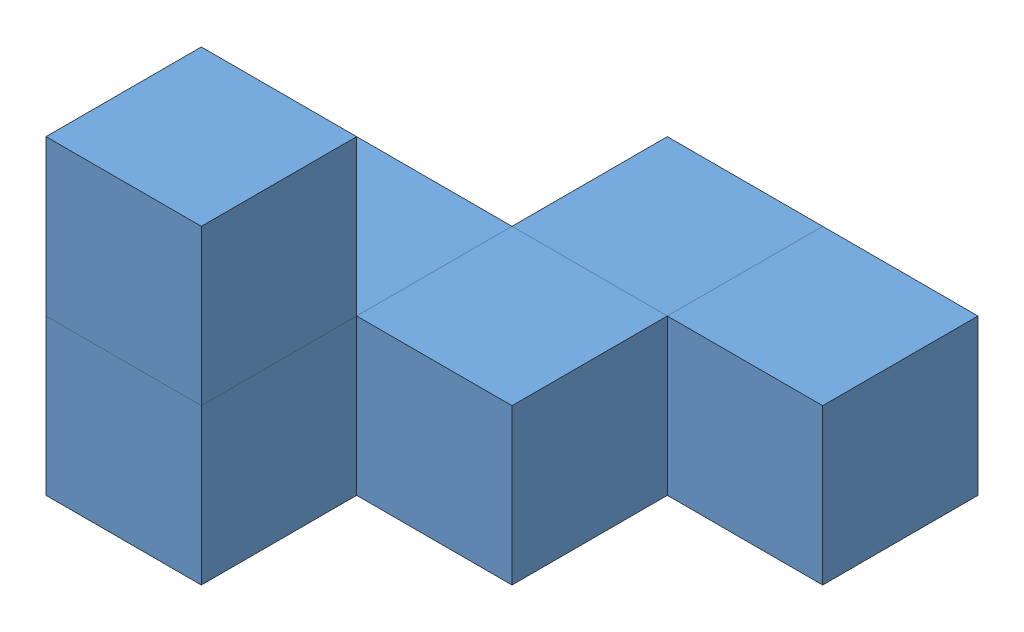
SolidWorks assembly Red Piece, configuration Default. Lengths in mm.
Overall size (60 40 60).
6 component instances, 1 part files, 18 mates.
Components (placement in the parent):
- cube-1: cube [Default] at (30 0 10) size (20 20 20)
- cube-2: cube [Default] at (30 0 30) size (20 20 20)
- cube-3: cube [Default] at (50 0 10) size (20 20 20)
- cube-4: cube [Default] at (10 0 50) size (20 20 20)
- cube-5: cube [Default] at (10 0 30) size (20 20 20)
- cube-6: cube [Default] at (10 20 50) size (20 20 20)
Mates (geometry in assembly coordinates):
- Coincident1: coincident aligned: plane of cube-1 through (40 20 20) normal (1 0 0); plane of cube-2 through (40 20 40) normal (1 0 0)
- Coincident2: coincident anti-aligned: plane of cube-1 through (40 20 20) normal (0 0 1); plane of cube-2 through (40 20 20) normal (0 0 -1)
- Coincident3: coincident aligned: plane of cube-1 through (30 20 10) normal (0 1 0); plane of cube-2 through (30 20 30) normal (0 1 0)
- Coincident4: coincident anti-aligned: plane of cube-2 through (20 20 40) normal (-1 0 0); plane of cube-5 through (20 20 40) normal (1 0 0)
- Coincident5: coincident aligned: plane of cube-2 through (40 20 40) normal (0 0 1); plane of cube-5 through (20 20 40) normal (0 0 1)
- Coincident6: coincident aligned: plane of cube-2 through (30 20 30) normal (0 1 0); plane of cube-5 through (10 20 30) normal (0 1 0)
- Coincident7: coincident: line of cube-2 through (40 20 20) axis (-1 0 0); plane of cube-3 through (60 20 20) normal (0 0 1)
- Coincident8: coincident anti-aligned: plane of cube-1 through (40 20 20) normal (1 0 0); plane of cube-3 through (40 20 20) normal (-1 0 0)
- Coincident9: coincident aligned: plane of cube-1 through (30 20 10) normal (0 1 0); plane of cube-3 through (50 20 10) normal (0 1 0)
- Coincident10: coincident anti-aligned: plane of cube-4 through (20 20 40) normal (0 0 -1); plane of cube-5 through (20 20 40) normal (0 0 1)
- Coincident11: coincident aligned: plane of cube-4 through (10 20 50) normal (0 1 0); plane of cube-5 through (10 20 30) normal (0 1 0)
- Coincident12: coincident aligned: plane of cube-4 through (0 20 60) normal (-1 0 0); plane of cube-5 through (0 20 40) normal (-1 0 0)
- Coincident13: coincident anti-aligned: plane of cube-4 through (10 20 50) normal (0 1 0); plane of cube-6 through (10 20 50) normal (0 -1 0)
- Coincident14: coincident aligned: plane of cube-4 through (0 20 60) normal (-1 0 0); plane of cube-6 through (0 40 60) normal (-1 0 0)
- Coincident15: coincident aligned: plane of cube-4 through (20 20 60) normal (0 0 1); plane of cube-6 through (20 40 60) normal (0 0 1)
- Coincident16: coincident anti-aligned: plane of cube-5 through (0 20 40) normal (-1 0 0); plane of assembly through (0 0 0) normal (1 0 0)
- Coincident17: coincident anti-aligned: plane of cube-1 through (40 20 0) normal (0 0 -1); plane of assembly through (0 0 0) normal (0 0 1)
- Coincident18: coincident anti-aligned: plane of cube-5 through (10 0 30) normal (0 -1 0); plane of assembly through (0 0 0) normal (0 1 0)
